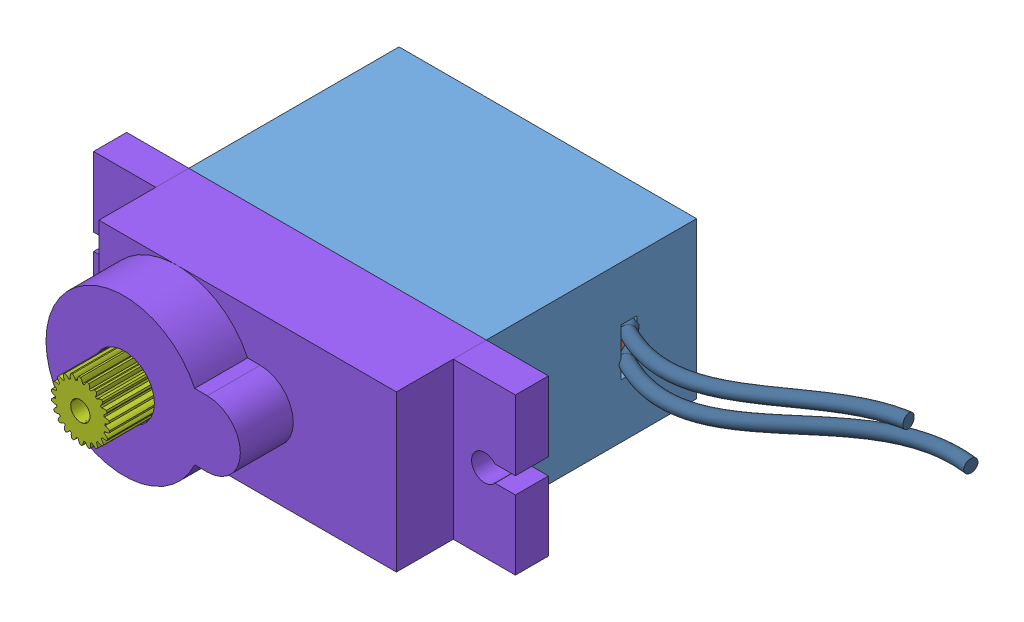
SolidWorks assembly servo-motor-montaj, configuration Varsayılan. Lengths in mm.
Overall size (45.89 13.05 32.84).
10 component instances, 10 part files, 0 mates.
Components (placement in the parent):
- lower cover-1: lower cover [Varsayılan] at (-10.9275 3.0017 -4.223) size (22.5 11.8 15.9)
- motor-1: motor [Varsayılan] at (-9.5275 2.9783 11.077) x (-0.99999 -0.004374 0) z (0 0 -1) size (7.83 7.83 13.56)
- feedback potentiometer-1: feedback potentiometer [Varsayılan] at (-9.0275 3.0017 11.177) x (-1 0 0) z (0 0 -1) size (7.71 7.36 13.7)
- Part6^servo motor assembley-1: Part6^servo motor assembley [Varsayılan] at (-10.9275 3.0017 11.177) x (-1 0 0) z (0 0 -1) size (1.5 1.5 10)
- Part7^servo motor assembley-1: Part7^servo motor assembley [Varsayılan] at (-9.517 2.6091 11.927) x (0.924877 -0.380266 0) z (0 0 1) size (10 10 5.7)
- Part8^servo motor assembley-1: Part8^servo motor assembley [Varsayılan] at (-9.3501 4.3681 11.477) x (0.966834 -0.255406 0) z (0 0 1) size (3.22 3.24 1.95)
- Part10^servo motor assembley-1: Part10^servo motor assembley [Varsayılan] at (-11.9047 8.7845 13.077) x (0.603146 0.797631 0) z (0 0 1) size (8.02 8.02 12.7)
- upper cover-1: upper cover [Varsayılan] at (-10.9275 3.0017 11.677) x (-1 0 0) z (0 0 1) size (31.9 11.8 10.8)
- Part16^servo motor assembley-1: Part16^servo motor assembley [Varsayılan] at (-10.9275 3.0017 -3.723) size (11.69 9.5 1.25)
- Part21^servo motor assembley-1: Part21^servo motor assembley [Varsayılan] at (-10.9275 -2.8983 -4.223) x (-1 0 0) z (0 -1 0) size (34.03 15.81 10.46)
